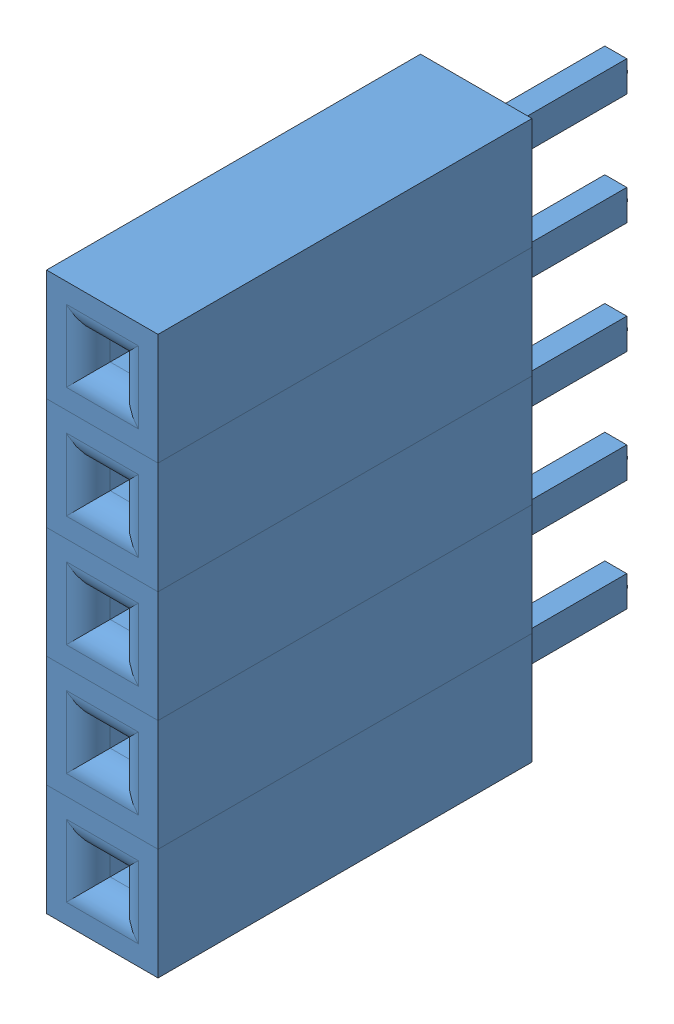
SolidWorks assembly Assem9, configuration Default. Lengths in mm.
Overall size (2.54 12.7 11.8).
5 component instances, 1 part files, 0 mates.
Components (placement in the parent):
- Female Header Pin-1: Female Header Pin [Default] at (-1.3014 1.3531 -2.8525) size (2.54 2.54 11.8)
- Female Header Pin-2: Female Header Pin [Default] at (-1.3014 3.8931 -2.8525) size (2.54 2.54 11.8)
- Female Header Pin-3: Female Header Pin [Default] at (-1.3014 6.4331 -2.8525) size (2.54 2.54 11.8)
- Female Header Pin-4: Female Header Pin [Default] at (-1.3014 8.9731 -2.8525) size (2.54 2.54 11.8)
- Female Header Pin-5: Female Header Pin [Default] at (-1.3014 11.5131 -2.8525) size (2.54 2.54 11.8)
